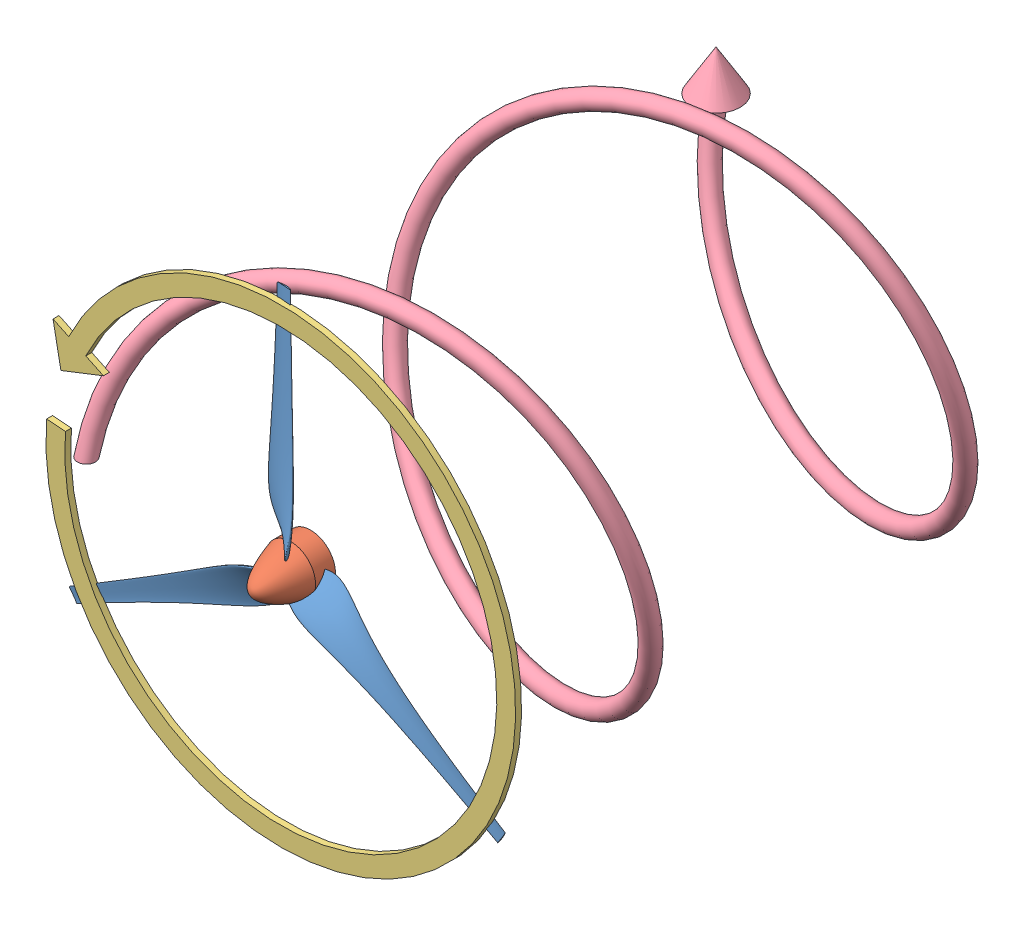
SolidWorks assembly celek. se šipkamiSLDASM, configuration Výchozí. Lengths in mm.
Overall size (2361.27 2430.64 3466.02).
6 component instances, 4 part files, 3 mates.
Components (placement in the parent):
- Nový list-2: Nový list [Výchozí] x (0 1 0) z (1 0 0) size (1368.75 127.07 260.66)
- Nový list-4: Nový list [Výchozí] x (0.866025 -0.5 0) z (-0.5 -0.866025 0) size (1368.75 127.07 260.66)
- Nový list-5: Nový list [Výchozí] x (-0.866025 -0.5 0) z (-0.5 0.866025 0) size (1368.75 127.07 260.66)
- Díl3-1: Díl3 [Výchozí] at origin size (250 250 300)
- Díl1^celek. se šipkamiSLDASM-1: Díl1^celek. se šipkamiSLDASM [Výchozí] at origin size (2361.27 2361.27 30) (virtual)
- Díl2^celek. se šipkamiSLDASM-1: Díl2^celek. se šipkamiSLDASM [Výchozí] at origin size (2225.54 2194.03 3331.28) (virtual)
Mates (geometry in assembly coordinates):
- Sjednocená2: coincident aligned: plane of Nový list-2; plane of assembly through (0 0 0) normal (0 0 1)
- Sjednocená3: coincident aligned: plane of Nový list-2; plane of assembly through (0 0 0) normal (0 1 0)
- Sjednocená4: coincident: point of Nový list-2; point of assembly
